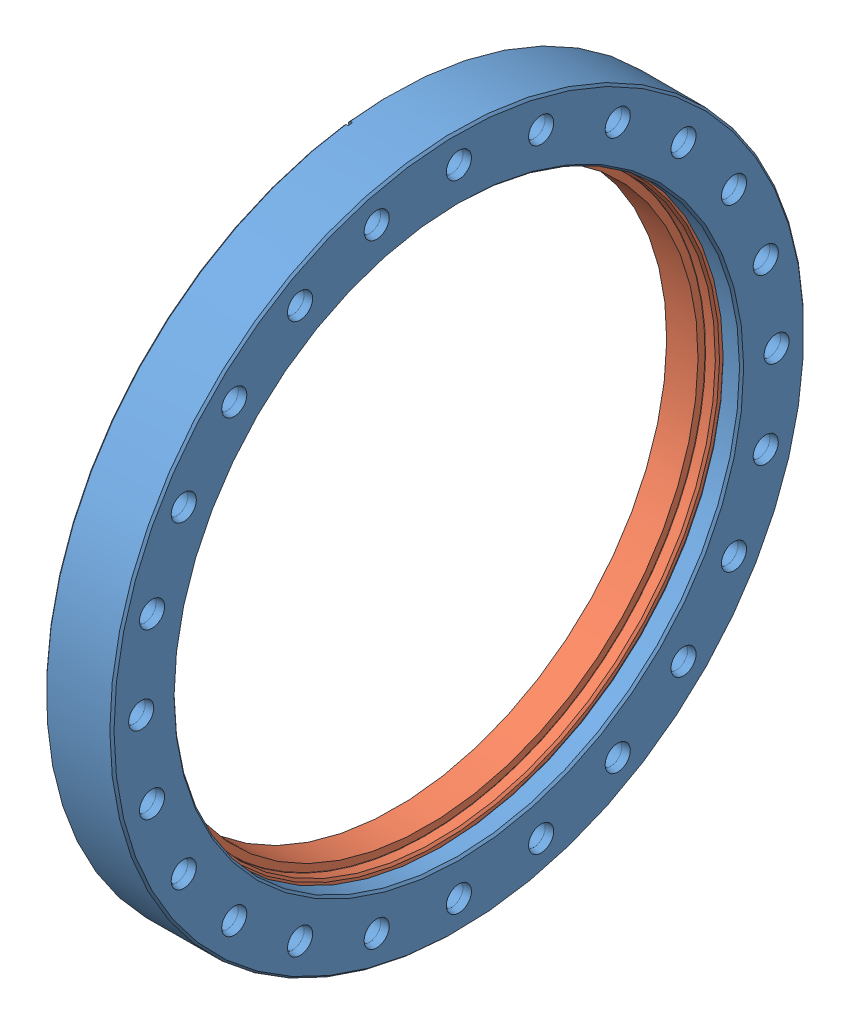
SolidWorks assembly 100033, configuration Default. Lengths in mm.
Overall size (24.65 253.24 253.24).
2 component instances, 2 part files, 2 mates.
Components (placement in the parent):
- 915009-1: 915009 [Default] at (67.6039 119.5576 210.6475) size (24.65 253.24 253.24)
- 910033-1: 910033 [Default] at (68.2643 119.5576 210.6475) x (1 0 0) z (0 0.010183 0.999948) size (16.43 221.95 221.95)
Mates (geometry in assembly coordinates):
- Concentric1: concentric: cylinder of 915009-1 through (67.6039 119.5576 210.6475) axis (-1 0 0) radius 126.619; cylinder of 910033-1 through (68.2643 119.5576 210.6475) axis (-1 0 0) radius 99.2124
- Coincident1: coincident anti-aligned: plane of 915009-1 through (84.7489 230.6826 210.6475) normal (-1 0 0); plane of 910033-1 through (84.7489 230.5245 209.5174) normal (1 0 0)
